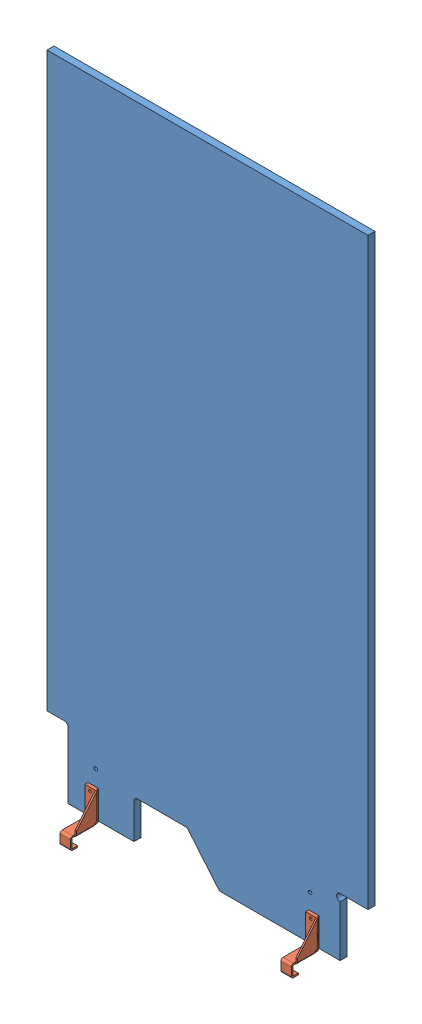
SolidWorks assembly 190225_GenericPlayfieldWidebody_1, configuration Default. Lengths in mm.
Overall size (584.2 1190.94 63.5).
3 component instances, 2 part files, 6 mates.
Components (placement in the parent):
- 190225_GenericPlayfieldWidebody_1-1: 190225_GenericPlayfieldWidebody_1 [Width_2300_Length_4600] at origin size (584.2 1168.4 12.7)
- 190216_HangerBracket_1-1: 190216_HangerBracket_1 [Default] at (93.6611 358.4575 -787.4) x (0 -1 0) z (-1 0 0) size (74.1 50.8 21.97)
- 190216_HangerBracket_1-2: 190216_HangerBracket_1 [Default] at (495.2986 358.4575 -787.4) x (0 -1 0) z (-1 0 0) size (74.1 50.8 21.97)
Mates (geometry in assembly coordinates):
- Concentric1: concentric anti-aligned: circle of 190216_HangerBracket_1-1
- Coincident2: coincident anti-aligned: plane of 190216_HangerBracket_1-1 through (74.6111 51.562 0) normal (0 0 -1)
- Parallel1: parallel aligned: unknown of 190216_HangerBracket_1-1
- Concentric2: concentric anti-aligned: unknown of 190216_HangerBracket_1-2
- Coincident4: coincident anti-aligned: unknown of 190216_HangerBracket_1-2
- Parallel2: parallel aligned: unknown of 190216_HangerBracket_1-2
